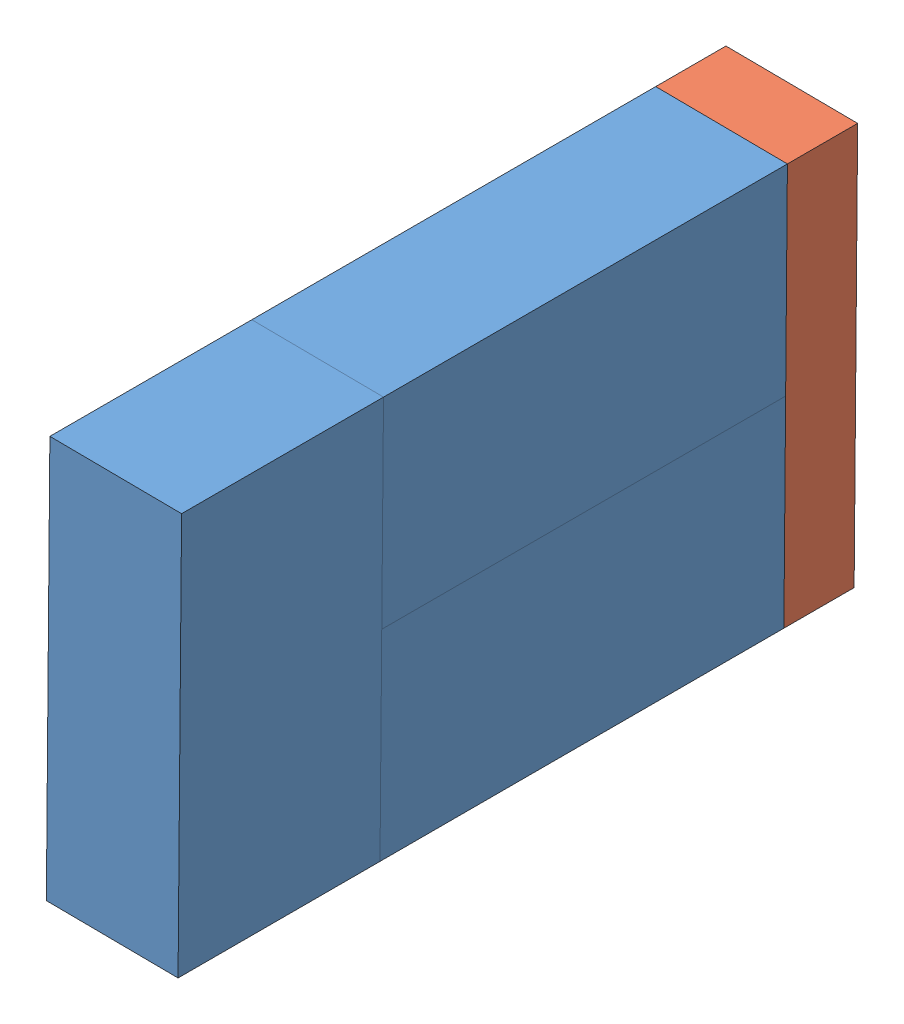
SolidWorks assembly Side Wall ext, configuration Default. Lengths in mm.
Overall size (77 230.65 385).
4 component instances, 2 part files, 6 mates.
Components (placement in the parent):
- Brick-Whole-1: Brick-Whole [Default] x (-0.008727 -0.999962 0) z (0 0 1) size (230 75 115)
- Brick-Whole-2: Brick-Whole [Default] at (0.5018 57.4978 -172.5) x (0 0 1) z (0.008727 0.999962 0) size (230 75 115)
- Brick-Whole-3: Brick-Whole [Default] at (-0.5018 -57.4978 -172.5) x (0 0 1) z (0.008727 0.999962 0) size (230 75 115)
- Brick-Whole-trimmed-1: Brick-Whole-trimmed [Default] at (0 0 -307.5) x (-0.008727 -0.999962 0) z (0 0 1) size (230 75 40)
Mates (geometry in assembly coordinates):
- Coincident1: coincident anti-aligned: line of Brick-Whole-1 through (36.495 -115.3229 -57.5) axis (0.008727 0.999962 0); line of Brick-Whole-3 through (37.4986 -0.3272 -57.5) axis (-0.008727 -0.999962 0)
- Coincident2: coincident aligned: line of Brick-Whole-1 through (36.495 -115.3229 -57.5) axis (-0.999962 0.008727 0); line of Brick-Whole-3 through (36.495 -115.3229 -57.5) axis (-0.999962 0.008727 0)
- Coincident5: coincident aligned: line of Brick-Whole-1 through (38.5021 114.6684 -57.5) axis (-0.999962 0.008727 0); line of Brick-Whole-2 through (38.5021 114.6684 -57.5) axis (-0.999962 0.008727 0)
- Coincident6: coincident anti-aligned: line of Brick-Whole-2 through (37.4986 -0.3272 -57.5) axis (0 0 -1); line of Brick-Whole-3 through (37.4986 -0.3272 -287.5) axis (0 0 1)
- Coincident7: coincident aligned: line of Brick-Whole-3 through (36.495 -115.3229 -287.5) axis (-0.999962 0.008727 0); line of Brick-Whole-trimmed-1 through (36.495 -115.3229 -287.5) axis (-0.999962 0.008727 0)
- Coincident8: coincident anti-aligned: line of Brick-Whole-3 through (36.495 -115.3229 -287.5) axis (0.008727 0.999962 0); line of Brick-Whole-trimmed-1 through (38.5021 114.6684 -287.5) axis (-0.008727 -0.999962 0)
